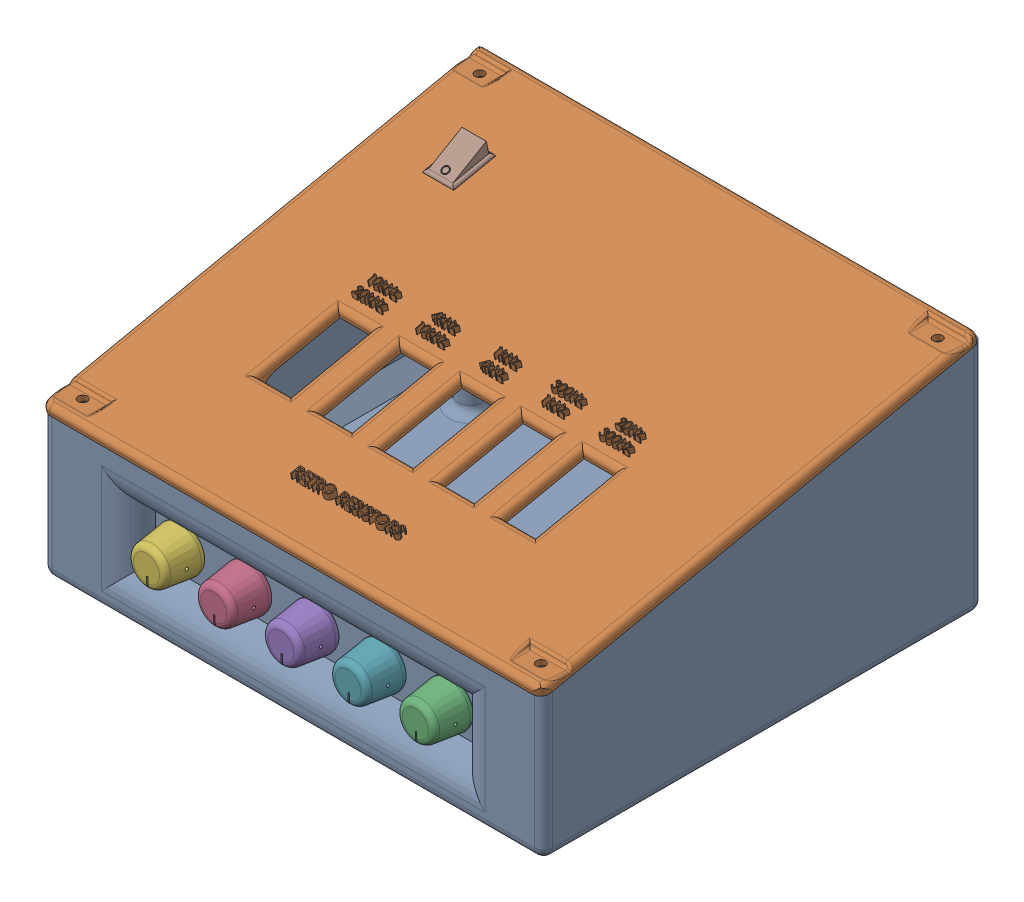
SolidWorks assembly Assem1.11, configuration Default. Lengths in mm.
Overall size (164.43 86.6 148.11).
8 component instances, 4 part files, 16 mates.
Components (placement in the parent):
- lab low-1: lab low [Default] at origin size (164 84 144)
- lab above-1: lab above [Default] at (0 -0.0971 0.4659) size (164.43 32.75 144.37)
- knob-1: knob [Default] at (124 26 -6) x (1 0 0) z (0 -1 0) size (14.69 12.11 14.69)
- knob-2: knob [Default] at (58 26 -6) x (1 0 0) z (0 -1 0) size (14.69 12.11 14.69)
- knob-4: knob [Default] at (80 26 -6) x (1 0 0) z (0 -1 0) size (14.69 12.11 14.69)
- knob-5: knob [Default] at (36 26 -6) x (1 0 0) z (0 -1 0) size (14.69 12.11 14.69)
- knob-6: knob [Default] at (102 26 -6) x (1 0 0) z (0 -1 0) size (14.69 12.11 14.69)
- SWITCH-1: SWITCH [Default] at (17.9638 74.8539 -102.5898) x (1 0 0) z (0 -0.203954 0.97898) size (10 5 14)
Mates (geometry in assembly coordinates):
- Coincident1: coincident aligned: plane of lab low-1 through (0 0 0) normal (0 0 1)
- Coincident2: coincident aligned: plane of lab low-1 through (0 0 0) normal (0 1 0)
- Coincident3: coincident aligned: plane of lab low-1 through (0 0 0) normal (1 0 0)
- Coincident7: coincident anti-aligned: plane of lab low-1 through (-2 80 -142) normal (0 0.97898 0.203954); plane of lab above-1 through (0 48.2224 10.5324) normal (0 -0.97898 -0.203954)
- Coincident8: coincident aligned: plane of lab low-1 through (162 0 0) normal (1 0 0); plane of lab above-1 through (162 -0.0971 0.4659) normal (1 0 0)
- Concentric1: concentric anti-aligned: cylinder of lab low-1 through (124 26 3) axis (0 0 -1) radius 4; cylinder of knob-1 through (124 26 -4) axis (0 0 1) radius 3
- Coincident9: coincident aligned: plane of lab low-1 through (0 0 -6) normal (0 0 1); circle of knob-1
- Concentric2: concentric anti-aligned: cylinder of lab low-1 through (102 26 3) axis (0 0 -1) radius 4; cylinder of knob-6 through (102 26 -4) axis (0 0 1) radius 3
- Concentric3: concentric anti-aligned: cylinder of lab low-1 through (80 26 3) axis (0 0 -1) radius 4; cylinder of knob-4 through (80 26 -4) axis (0 0 1) radius 3
- Concentric4: concentric anti-aligned: cylinder of lab low-1 through (58 26 3) axis (0 0 -1) radius 4; cylinder of knob-2 through (58 26 -4) axis (0 0 1) radius 3
- Concentric5: concentric anti-aligned: cylinder of lab low-1 through (36 26 3) axis (0 0 -1) radius 4; cylinder of knob-5 through (36 26 -4) axis (0 0 1) radius 3
- Coincident10: coincident aligned: plane of lab low-1 through (0 0 -6) normal (0 0 1); circle of knob-6
- Coincident11: coincident aligned: plane of lab low-1 through (0 0 -6) normal (0 0 1); circle of knob-4
- Coincident12: coincident aligned: plane of lab low-1 through (0 0 -6) normal (0 0 1); circle of knob-2
- Coincident13: coincident aligned: plane of lab low-1 through (0 0 -6) normal (0 0 1); circle of knob-5
- Coincident14: coincident anti-aligned: plane of lab above-1 through (0 51.1594 11.1443) normal (0 0.97898 0.203954); plane of SWITCH-1 through (17.9638 74.8539 -102.5898) normal (0 -0.97898 -0.203954)
